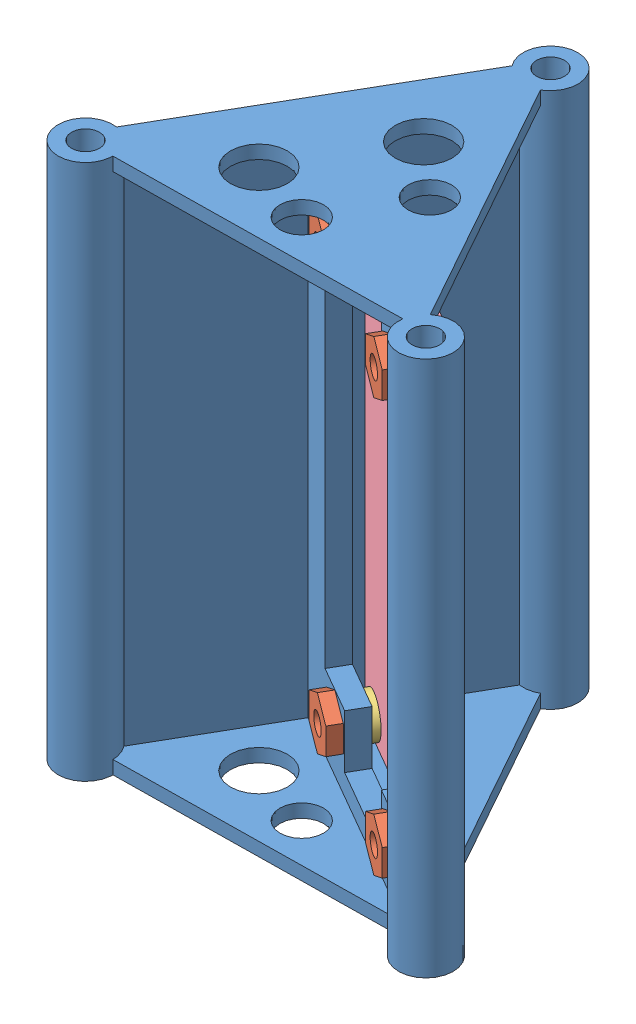
SolidWorks assembly S1B_Sensor_Stack_Assy, configuration Default. Lengths in mm.
Overall size (58.99 80 52.18).
10 component instances, 4 part files, 19 mates.
Components (placement in the parent):
- S1B_Sensor_Stack_T_Mount_A2-1: S1B_Sensor_Stack_T_Mount_A2 [Default] at (9.5389 -1.0891 74.5991) size (58.99 80 52.18)
- S1B_6.86mm_Nut_3mm_Hole-1: S1B_6.86mm_Nut_3mm_Hole [Default] at (6.8862 79.7859 74.7996) x (0.75 0.5 0.433013) z (0.433013 -0.866025 0.25) size (7.92 1.91 6.86)
- S1B_Ruber_Washer_3mm-1: S1B_Ruber_Washer_3mm [Default] at (28.3048 79.7859 83.7015) x (0.75 -0.5 0.433013) z (0.433013 0.866025 0.25) size (6 1.25 6)
- S1B_Ruber_Washer_3mm-2: S1B_Ruber_Washer_3mm [Default] at (8.3862 79.7859 72.2015) x (0.75 -0.5 0.433013) z (0.433013 0.866025 0.25) size (6 1.25 6)
- S1B_Ruber_Washer_3mm-3: S1B_Ruber_Washer_3mm [Default] at (28.3048 18.0359 83.7015) x (0.75 -0.5 0.433013) z (0.433013 0.866025 0.25) size (6 1.25 6)
- S1B_Ruber_Washer_3mm-4: S1B_Ruber_Washer_3mm [Default] at (8.3862 18.0359 72.2015) x (0.75 -0.5 0.433013) z (0.433013 0.866025 0.25) size (6 1.25 6)
- S1B_6.86mm_Nut_3mm_Hole-3: S1B_6.86mm_Nut_3mm_Hole [Default] at (26.8048 18.0359 86.2996) x (0.75 0.5 0.433013) z (0.433013 -0.866025 0.25) size (7.92 1.91 6.86)
- S1B_6.86mm_Nut_3mm_Hole-4: S1B_6.86mm_Nut_3mm_Hole [Default] at (6.8862 18.0359 74.7996) x (0.75 0.5 0.433013) z (0.433013 -0.866025 0.25) size (7.92 1.91 6.86)
- S1B_6.86mm_Nut_3mm_Hole-2: S1B_6.86mm_Nut_3mm_Hole [Default] at (26.8048 79.7859 86.2996) x (0.75 0.5 0.433013) z (0.433013 -0.866025 0.25) size (7.92 1.91 6.86)
- S1B_Sensor_PCB-1: S1B_Sensor_PCB [Default] at (32.9609 14.7859 82.637) x (0 1 0) z (0.866025 0 0.5) size (68.25 2 30)
Mates (geometry in assembly coordinates):
- Coincident1: coincident aligned: plane of Ruber_Washer_3mm-1 through (28.3048 79.7859 83.7015) normal (-0.5 0 0.866025); plane of Ruber_Washer_3mm-2 through (8.3862 79.7859 72.2015) normal (-0.5 0 0.866025)
- Coincident2: coincident aligned: plane of Ruber_Washer_3mm-1 through (28.3048 79.7859 83.7015) normal (-0.5 0 0.866025); plane of Ruber_Washer_3mm-4 through (8.3862 18.0359 72.2015) normal (-0.5 0 0.866025)
- Coincident3: coincident aligned: plane of Ruber_Washer_3mm-3 through (28.3048 18.0359 83.7015) normal (-0.5 0 0.866025); plane of Ruber_Washer_3mm-4 through (8.3862 18.0359 72.2015) normal (-0.5 0 0.866025)
- Coincident4: coincident anti-aligned: plane of S1B_Sensor_Stack_T_Mount_A2-1 through (10.2889 88.9109 73.3001) normal (0.5 0 -0.866025); plane of Ruber_Washer_3mm-2 through (8.3862 79.7859 72.2015) normal (-0.5 0 0.866025)
- Concentric1: concentric anti-aligned: circle of Sensor_Stack_T_Mount_A2-1; circle of Ruber_Washer_3mm-2
- Concentric2: concentric anti-aligned: circle of Sensor_Stack_T_Mount_A2-1; circle of Ruber_Washer_3mm-3
- Concentric3: concentric anti-aligned: circle of Sensor_Stack_T_Mount_A2-1; circle of Ruber_Washer_3mm-4
- Concentric4: concentric anti-aligned: circle of Sensor_Stack_T_Mount_A2-1; circle of Ruber_Washer_3mm-1
- Coincident5: coincident aligned: plane of 6.86mm_Nut_3mm_Hole-1 through (6.8862 79.7859 74.7996) normal (0.5 0 -0.866025); plane of 6.86mm_Nut_3mm_Hole-4 through (6.8862 18.0359 74.7996) normal (0.5 0 -0.866025)
- Coincident6: coincident aligned: plane of 6.86mm_Nut_3mm_Hole-1 through (6.8862 79.7859 74.7996) normal (0.5 0 -0.866025); plane of 6.86mm_Nut_3mm_Hole-2 through (26.8048 79.7859 86.2996) normal (0.5 0 -0.866025)
- Coincident7: coincident aligned: plane of 6.86mm_Nut_3mm_Hole-2 through (26.8048 79.7859 86.2996) normal (0.5 0 -0.866025); plane of 6.86mm_Nut_3mm_Hole-3 through (26.8048 18.0359 86.2996) normal (0.5 0 -0.866025)
- Coincident8: coincident anti-aligned: plane of S1B_Sensor_Stack_T_Mount_A2-1 through (8.7889 88.9109 75.8981) normal (-0.5 0 0.866025); plane of 6.86mm_Nut_3mm_Hole-4 through (6.8862 18.0359 74.7996) normal (0.5 0 -0.866025)
- Concentric5: concentric aligned: circle of Sensor_Stack_T_Mount_A2-1; circle of 6.86mm_Nut_3mm_Hole-4
- Concentric7: concentric aligned: circle of Sensor_Stack_T_Mount_A2-1; circle of 6.86mm_Nut_3mm_Hole-3
- Concentric8: concentric aligned: circle of Sensor_Stack_T_Mount_A2-1; circle of 6.86mm_Nut_3mm_Hole-2
- Concentric9: concentric aligned: circle of Sensor_Stack_T_Mount_A2-1; circle of 6.86mm_Nut_3mm_Hole-1
- Coincident9: coincident anti-aligned: plane of Ruber_Washer_3mm-4 through (9.0112 18.0359 71.119) normal (0.5 0 -0.866025); plane of Sensor_PCB-1 through (31.9609 14.7859 84.369) normal (-0.5 0 0.866025)
- Concentric10: concentric anti-aligned: circle of Ruber_Washer_3mm-2; circle of Sensor_PCB-1
- Concentric11: concentric aligned: cylinder of S1B_Sensor_Stack_T_Mount_A2-1 through (30.6029 18.0359 79.7211) axis (-0.5 0 0.866025) radius 1.625; circle of Sensor_PCB-1
